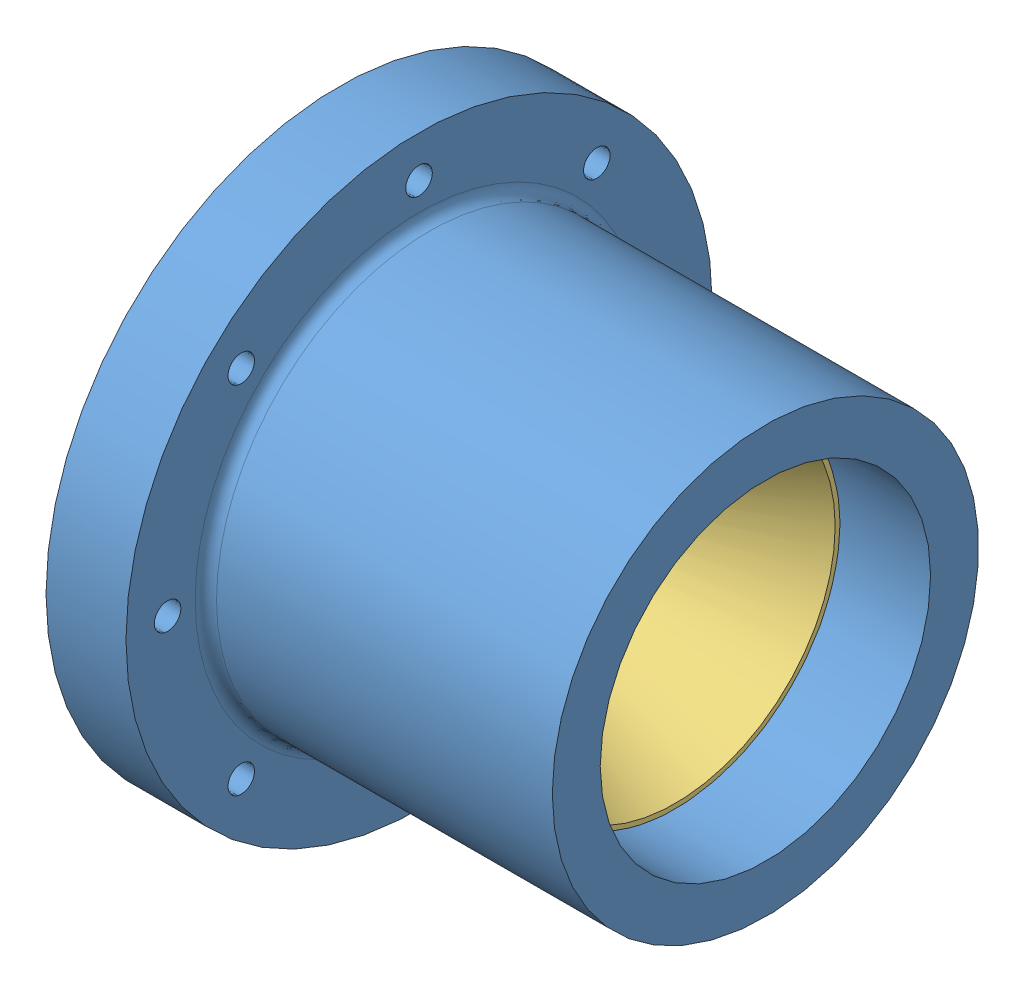
SolidWorks assembly NozzleModularAssy, configuration Default. Lengths in mm.
Overall size (101.6 139.7 139.7).
11 component instances, 5 part files, 22 mates.
Components (placement in the parent):
- ModularNozzleDesign-1: ModularNozzleDesign [Default] at origin size (101.6 139.7 139.7)
- UpperNozzleInsert-1: UpperNozzleInsert [Default] at (-12.6162 0 0) size (22.86 101.6 101.6)
- LowerNozzleInsert-1: LowerNozzleInsert [Default] at (18.7559 0 0) x (0 -1 0) z (0 0 -1) size (78.74 57.15 78.74)
- socket head cap screw_ai-3: socket head cap screw_ai [HX-SHCS 0.164-32x0.625x0.625-N] at (-13.5996 25.4 0) x (1 0 0) z (0 -0.190004 0.981783) size (20.04 6.86 6.86)
- socket head cap screw_ai-4: socket head cap screw_ai [HX-SHCS 0.164-32x0.625x0.625-N] at (-13.5996 0 25.4) x (1 0 0) z (0 -0.134752 -0.990879) size (20.04 6.86 6.86)
- socket head cap screw_ai-5: socket head cap screw_ai [HX-SHCS 0.164-32x0.625x0.625-N] at (-13.5996 -25.4 0) x (1 0 0) z (0 -0.02703 0.999635) size (20.04 6.86 6.86)
- socket head cap screw_ai-6: socket head cap screw_ai [HX-SHCS 0.164-32x0.625x0.625-N] at (-13.5996 0 -25.4) x (1 0 0) z (0 0.188031 0.982163) size (20.04 6.86 6.86)
- dowel pin (hardened production)_ai-2: dowel pin (hardened production)_ai [ASME B18.8.2 - 0.1877x0.625] at (-30.1096 44.45 0) size (15.88 4.77 4.77)
- dowel pin (hardened production)_ai-3: dowel pin (hardened production)_ai [ASME B18.8.2 - 0.1877x0.625] at (-30.1096 0 -44.45) size (15.88 4.77 4.77)
- dowel pin (hardened production)_ai-4: dowel pin (hardened production)_ai [ASME B18.8.2 - 0.1877x0.625] at (-30.1096 -44.45 0) size (15.88 4.77 4.77)
- dowel pin (hardened production)_ai-5: dowel pin (hardened production)_ai [ASME B18.8.2 - 0.1877x0.625] at (-30.1096 0 44.45) size (15.88 4.77 4.77)
Mates (geometry in assembly coordinates):
- Coincident1: coincident: plane of ModularNozzleDesign-1 through (-13.5996 39.37 0) normal (-1 0 0); plane of UpperNozzleInsert-1 through (-13.5996 0 0) normal (1 0 0)
- Concentric1: concentric: cylinder of ModularNozzleDesign-1 through (0 0 0) axis (-1 0 0) radius 39.37; cylinder of UpperNozzleInsert-1 through (6.3196 0 0) axis (1 0 0) radius 39.37
- Concentric2: concentric: cylinder of ModularNozzleDesign-1 through (-26.9346 -44.45 0) axis (-1 0 0) radius 2.3813; cylinder of UpperNozzleInsert-1 through (-30.1096 -44.45 0) axis (-1 0 0) radius 2.3813
- Concentric3: concentric: cylinder of ModularNozzleDesign-1 through (0 0 0) axis (-1 0 0) radius 39.37; cylinder of LowerNozzleInsert-1 through (-14.7388 0 0) axis (-1 0 0) radius 39.37
- Concentric4: concentric: cylinder of ModularNozzleDesign-1 through (-13.5996 0 -25.4) axis (-1 0 0) radius 2.2479; circle of LowerNozzleInsert-1
- Coincident2: coincident: plane of ModularNozzleDesign-1 through (-0.8996 11.43 0) normal (1 0 0); plane of LowerNozzleInsert-1 through (-0.8996 39.37 0) normal (-1 0 0)
- Concentric5: concentric: cylinder of ModularNozzleDesign-1 through (-13.5996 25.4 0) axis (-1 0 0) radius 2.2479; cylinder of socket head cap screw_ai-3 through (-45.3496 25.4 0) axis (-1 0 0) radius 3.429
- Concentric6: concentric: cylinder of ModularNozzleDesign-1 through (-13.5996 0 25.4) axis (-1 0 0) radius 2.2479; cylinder of socket head cap screw_ai-4 through (-45.3496 0 25.4) axis (-1 0 0) radius 3.429
- Concentric7: concentric: cylinder of ModularNozzleDesign-1 through (-13.5996 -25.4 0) axis (-1 0 0) radius 2.2479; cylinder of socket head cap screw_ai-5 through (-45.3496 -25.4 0) axis (-1 0 0) radius 3.429
- Concentric8: concentric: cylinder of ModularNozzleDesign-1 through (-13.5996 0 -25.4) axis (-1 0 0) radius 2.2479; cylinder of socket head cap screw_ai-6 through (-45.3496 0 -25.4) axis (-1 0 0) radius 3.429
- Coincident3: coincident: plane of ModularNozzleDesign-1 through (-9.434 3.9688 -25.4) normal (-1 0 0); plane of socket head cap screw_ai-6 through (-9.434 3.3678 -26.0448) normal (1 0 0)
- Coincident4: coincident: plane of ModularNozzleDesign-1 through (-9.434 29.3687 0) normal (-1 0 0); plane of socket head cap screw_ai-3 through (-9.434 28.7665 0.6515) normal (1 0 0)
- Coincident5: coincident: plane of ModularNozzleDesign-1 through (-9.434 3.9688 25.4) normal (-1 0 0); plane of socket head cap screw_ai-4 through (-9.434 -3.3977 25.8621) normal (1 0 0)
- Coincident6: coincident: plane of ModularNozzleDesign-1 through (-9.434 -21.4312 0) normal (-1 0 0); plane of socket head cap screw_ai-5 through (-9.434 -21.9723 0.0927) normal (1 0 0)
- Concentric9: concentric: cylinder of UpperNozzleInsert-1 through (-30.1096 44.45 0) axis (-1 0 0) radius 2.3813; cylinder of dowel pin (hardened production)_ai-2 through (-36.4596 44.45 0) axis (-1 0 0) radius 2.3838
- Concentric10: concentric: cylinder of UpperNozzleInsert-1 through (-30.1096 0 -44.45) axis (-1 0 0) radius 2.3813; cylinder of dowel pin (hardened production)_ai-3 through (-36.4596 0 -44.45) axis (-1 0 0) radius 2.3838
- Concentric11: concentric: cylinder of UpperNozzleInsert-1 through (-30.1096 -44.45 0) axis (-1 0 0) radius 2.3813; cylinder of dowel pin (hardened production)_ai-4 through (-36.4596 -44.45 0) axis (-1 0 0) radius 2.3838
- Concentric12: concentric: cylinder of UpperNozzleInsert-1 through (-30.1096 0 44.45) axis (-1 0 0) radius 2.3813; cylinder of dowel pin (hardened production)_ai-5 through (-36.4596 0 44.45) axis (-1 0 0) radius 2.3838
- Coincident7: coincident: plane of UpperNozzleInsert-1 through (-30.1096 -39.37 0) normal (-1 0 0); plane of dowel pin (hardened production)_ai-3 through (-30.1096 1.8758 -44.45) normal (-1 0 0)
- Coincident8: coincident: plane of UpperNozzleInsert-1 through (-30.1096 -39.37 0) normal (-1 0 0); plane of dowel pin (hardened production)_ai-4 through (-30.1096 -42.5742 0) normal (-1 0 0)
- Coincident9: coincident: plane of UpperNozzleInsert-1 through (-30.1096 -39.37 0) normal (-1 0 0); plane of dowel pin (hardened production)_ai-2 through (-30.1096 46.3258 0) normal (-1 0 0)
- Coincident10: coincident: plane of UpperNozzleInsert-1 through (-30.1096 -39.37 0) normal (-1 0 0); plane of dowel pin (hardened production)_ai-5 through (-30.1096 1.8758 44.45) normal (-1 0 0)
